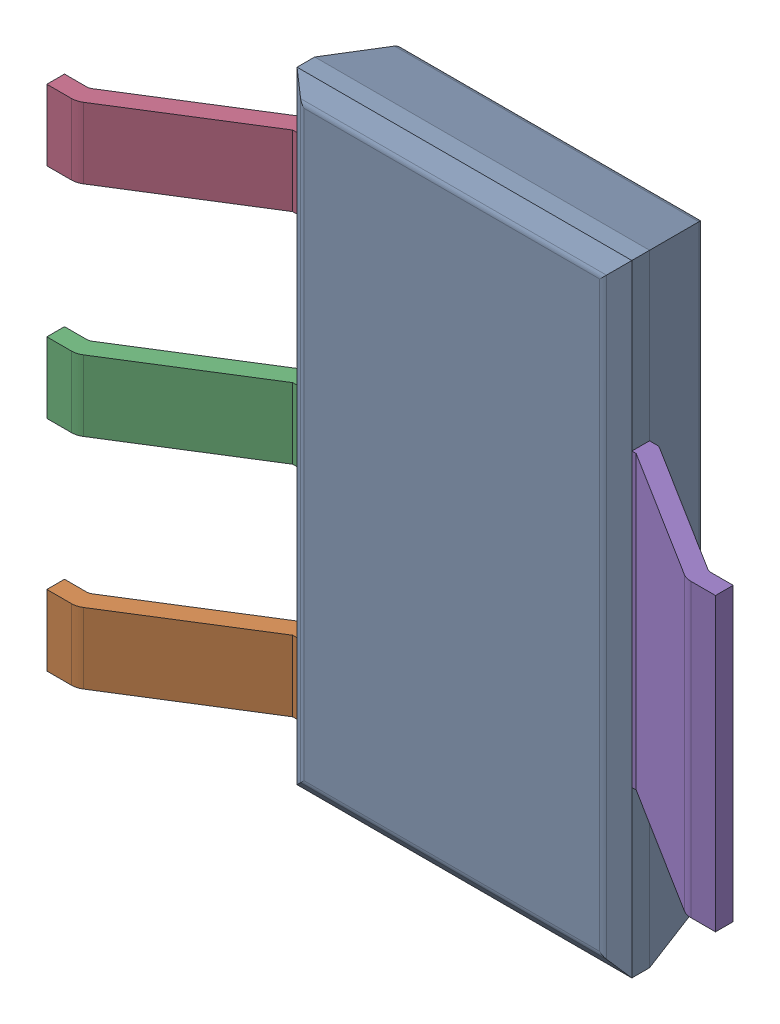
SolidWorks assembly IC7_3.step, configuration Default. Lengths in mm.
Overall size (7 6.51 1.8).
4 component instances, 3 part files, 0 mates.
Components (placement in the parent):
- 6383673440.step-1: 6383673440.step [Default] at (132.032 106.807 -1.1227) x (1 0 0) z (0 0 -1) size (7 6.51 1.8)
  - Body_9.step-5: Body_9.step [Default] at origin size (3.5 6.51 1.06)
  - PinsArrayL_3.step-5: PinsArrayL_3.step [Default] at origin size (1.75 5.32 1.06)
  - FilletPinR_3.step-5: FilletPinR_3.step [Default] at origin size (1.75 3.05 1.06)
